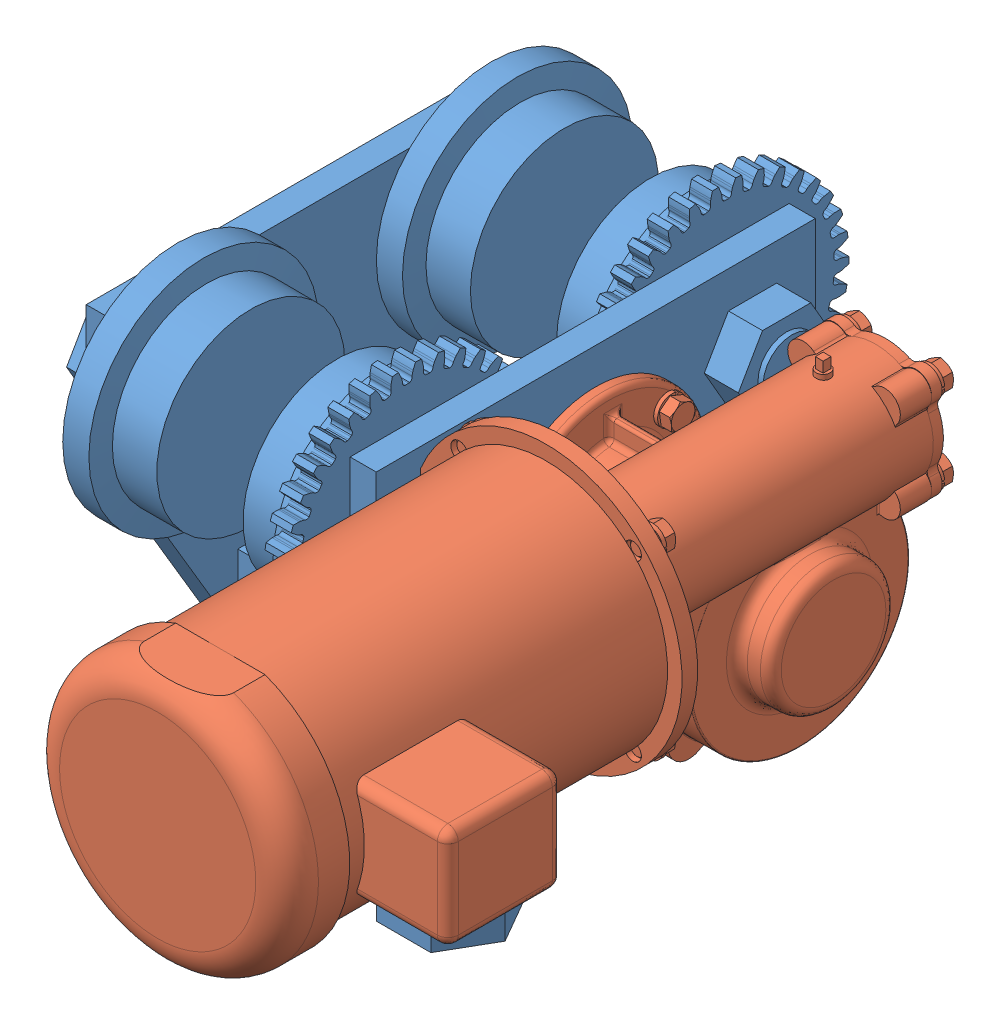
SolidWorks assembly M2631C-LH, configuration Default. Lengths in mm.
Overall size (427.7 413.65 540.72).
2 component instances, 2 part files, 3 mates.
Components (placement in the parent):
- Copy of M2631C-TROLLEY-SECTION^M2631C-LH-1: Copy of M2631C-TROLLEY-SECTION^M2631C-LH [4.0625 PAT TRACK] at origin size (223.93 375.83 342.81) (virtual)
- Copy of SDT GEAR REDUCER LH^M2631C-LH-1: Copy of SDT GEAR REDUCER LH^M2631C-LH [Default] at (191.2747 120.2538 0) x (-1 0 0) z (0 0 -1) size (229.23 225.42 451.54) (virtual)
Mates (geometry in assembly coordinates):
- Coincident2: coincident aligned: plane of Copy of M2631C-TROLLEY-SECTION^M2631C-LH-1 through (0 120.2538 0) normal (0 1 0); plane of Copy of SDT GEAR REDUCER LH^M2631C-LH-1
- Coincident3: coincident anti-aligned: plane of Copy of M2631C-TROLLEY-SECTION^M2631C-LH-1 through (0 0 0) normal (0 0 1); plane of Copy of SDT GEAR REDUCER LH^M2631C-LH-1 through (191.2747 120.2538 0) normal (0 0 -1)
- Distance1: distance = 14.2875 mm aligned: plane of Copy of M2631C-TROLLEY-SECTION^M2631C-LH-1 through (72.2122 0 -133.35) normal (-1 0 0); plane of Copy of SDT GEAR REDUCER LH^M2631C-LH-1 through (86.4997 120.2538 0) normal (-1 0 0)
